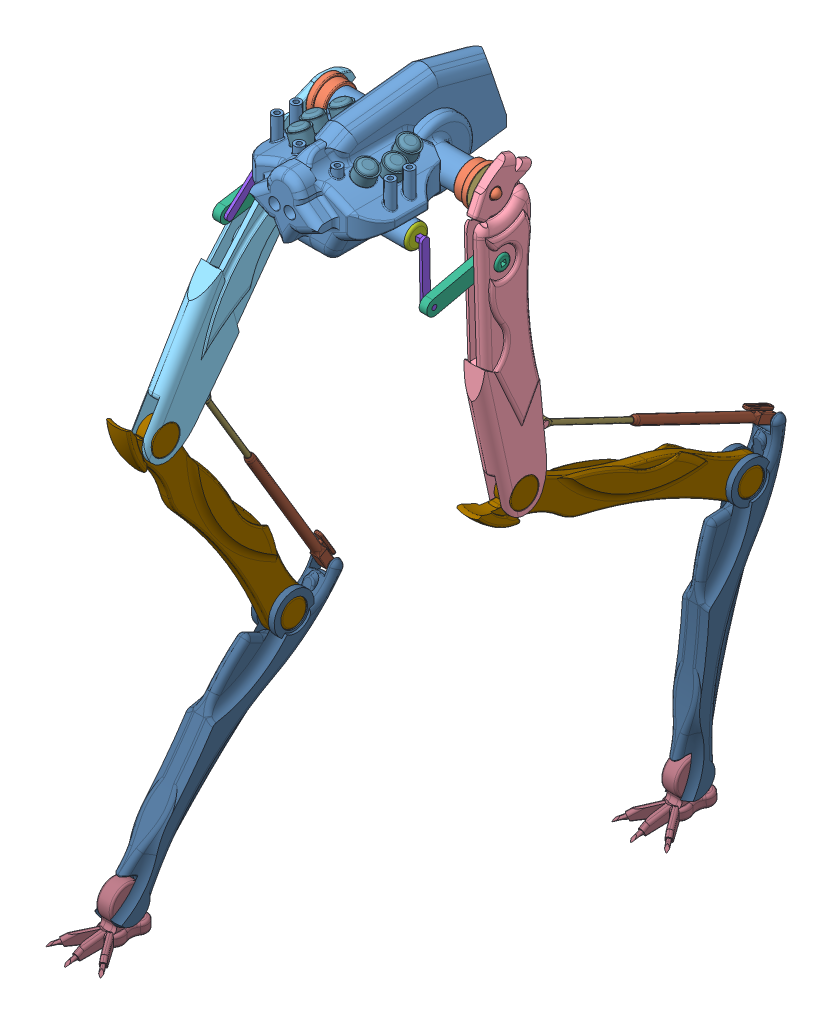
SolidWorks assembly canine rear end assembly, configuration Default. Lengths in mm.
Overall size (298.64 923.84 728.2).
29 component instances, 14 part files, 50 mates.
Components (placement in the parent):
- hind quarters-1: hind quarters [Default] at origin size (198.12 141.12 290.2)
- rear brushless hub motor-1: rear brushless hub motor [Default] at (86.36 -5.0738 -138.7243) x (1 0 0) z (0 -0.469696 0.882828) size (39.37 50.8 50.8)
- rear brushless hub motor cap-1: rear brushless hub motor cap [Default] at (106.68 -5.0738 -138.7243) x (1 0 0) z (0 0.469696 -0.882828) size (2.92 50.8 50.8)
- rear brushless hub motor cap-2: rear brushless hub motor cap [Default] at (-106.68 -5.0738 -138.7243) x (-1 0 0) z (0 0.867474 0.497482) size (2.92 50.8 50.8)
- rear brushless hub motor-2: rear brushless hub motor [Default] at (-86.36 -5.0738 -138.7243) x (-1 0 0) z (0 -0.867474 -0.497482) size (39.37 50.8 50.8)
- upper rear left leg-1: upper rear left leg [Default] at (107.315 -5.0738 -138.7243) x (1 0 0) z (0 -0.213473 0.976949) size (35.47 408.3 128.58)
- upper rear right leg-1: upper rear right leg [Default] at (-81.915 -5.0738 -138.7243) x (1 0 0) z (0 0.508175 0.861254) size (35.47 408.3 128.58)
- upper rear leg slider control bar-1: upper rear leg slider control bar [Default] at (110.236 -82.5296 -141.2052) x (1 0 0) z (0 -0.218855 0.975757) size (27.94 20.32 101.6)
- rear leg motion controller-1: rear leg motion controller [Default] at (66.04 -29.21 -60.599) x (1 0 0) z (0 -0.018232 0.999834) size (28.55 30.48 30.48)
- rear leg motion control rod-1: rear leg motion control rod [Default] at (102.108 -29.21 -60.599) x (1 0 0) z (0 0.999834 0.018232) size (26.67 10.16 81.28)
- rear leg motion controller-2: rear leg motion controller [Default] at (-66.04 -29.21 -60.599) x (-1 0 0) z (0 0.667442 -0.744662) size (28.55 30.48 30.48)
- rear leg motion control rod-2: rear leg motion control rod [Default] at (-102.108 -29.21 -60.599) x (-1 0 0) z (0 0.667442 -0.744662) size (26.67 10.16 81.28)
- upper rear leg slider control bar-2: upper rear leg slider control bar [Default] at (-110.236 -63.5304 -87.8482) x (-1 0 0) z (0 -0.161762 0.98683) size (27.94 20.32 101.6)
- middle rear leg-1: middle rear leg [Default] at (112.776 -362.7527 -170.5598) x (1 0 0) z (0 -0.909563 0.415567) size (41.3 413.23 74.4)
- middle rear leg-2: middle rear leg [Default] at (-112.776 -288.8817 81.2774) x (1 0 0) z (0 -0.513146 0.858301) size (41.3 413.23 74.4)
- lower rear leg-1: lower rear leg [Default] at (112.776 -499.973 -470.8973) x (1 0 0) z (0 0.252017 0.967723) size (49.71 405.22 76.89)
- lower rear leg-2: lower rear leg [Default] at (-112.776 -572.2927 -88.1635) x (1 0 0) z (0 0.701414 0.712754) size (49.71 405.22 76.89)
- lower rear leg motion sensor controller-1: lower rear leg motion sensor controller [Default] at (112.776 -451.3664 -510.4118) x (1 0 0) z (0 -0.902171 0.431378) size (20.32 209.55 18.41)
- lower rear leg motion sensor controller-2: lower rear leg motion sensor controller [Default] at (-112.776 -549.8979 -146.6654) x (1 0 0) z (0 -0.512749 0.858539) size (20.32 209.55 18.41)
- lower rear leg control rod-1: lower rear leg control rod [Default] at (112.776 -307.16 -208.8231) x (1 0 0) z (0 0.431378 0.902171) size (6.74 11.43 217.51)
- lower rear leg control rod-2: lower rear leg control rod [Default] at (-112.776 -276.3555 16.7037) x (1 0 0) z (0 0.858539 0.512749) size (6.74 11.43 217.51)
- rear claws-1: rear claws [Default] at (112.776 -806.1061 -398.4196) x (1 0 0) z (0 -0.032832 0.999461) size (73.09 64.37 105.72)
- rear claws-2: rear claws [Default] at (-112.776 -801.3851 127.4454) size (73.09 64.37 105.72)
- fluids container-1: fluids container [Default] at (25.9582 -13.2367 -42.5839) x (0.929939 -0.367713 -0.000069) z (-0.000069 -0.000362 1) size (26.67 57.15 26.67)
- fluids container-2: fluids container [Default] at (35.4101 -16.9633 -70.5239) x (0.929939 -0.367713 -0.000069) z (-0.000069 -0.000362 1) size (26.67 57.15 26.67)
- fluids container-3: fluids container [Default] at (25.9656 -13.2179 -98.4639) x (0.929939 -0.367713 -0.000069) z (-0.000069 -0.000362 1) size (26.67 57.15 26.67)
- fluids container-4: fluids container [Default] at (-25.9656 -13.2179 -98.4639) x (0.929939 0.367713 0.000069) z (0.000069 -0.000362 1) size (26.67 57.15 26.67)
- fluids container-5: fluids container [Default] at (-35.4101 -16.9633 -70.5239) x (0.929939 0.367713 0.000069) z (0.000069 -0.000362 1) size (26.67 57.15 26.67)
- fluids container-6: fluids container [Default] at (-25.9582 -13.2367 -42.5839) x (0.929939 0.367713 0.000069) z (0.000069 -0.000362 1) size (26.67 57.15 26.67)
Mates (geometry in assembly coordinates):
- Coincident1: coordinate: point of hind quarters-1; point of assembly
- Coincident2: coincident aligned: circle of hind quarters-1; circle of rear brushless hub motor-1
- Coincident3: coincident anti-aligned: circle of rear brushless hub motor-1; circle of rear brushless hub motor cap-1
- Coincident4: coincident anti-aligned: cylinder of rear brushless hub motor-1 through (119.38 -5.0738 -138.7243) axis (-1 0 0) radius 7.62; circle of rear brushless hub motor cap-1
- Coincident5: coincident anti-aligned: circle of hind quarters-1; circle of rear brushless hub motor-2
- Coincident6: coincident anti-aligned: circle of rear brushless hub motor cap-2; circle of rear brushless hub motor-2
- Concentric1: concentric anti-aligned: circle of rear brushless hub motor cap-2; cylinder of rear brushless hub motor-2 through (-119.38 -5.0738 -138.7243) axis (1 0 0) radius 7.62
- Concentric3: concentric aligned: cylinder of rear brushless hub motor-1 through (119.38 -5.0738 -138.7243) axis (-1 0 0) radius 7.62; cylinder of upper rear left leg-1 through (119.507 -5.0738 -138.7243) axis (-1 0 0) radius 7.62
- Coincident8: coincident anti-aligned: plane of rear brushless hub motor cap-1 through (107.315 -5.0738 -138.7243) normal (1 0 0); plane of upper rear left leg-1 through (107.315 -5.0738 -138.7243) normal (-1 0 0)
- Concentric4: concentric aligned: cylinder of rear brushless hub motor-2 through (-119.38 -5.0738 -138.7243) axis (1 0 0) radius 7.62; cylinder of upper rear right leg-1 through (-119.507 -5.0738 -138.7243) axis (1 0 0) radius 7.62
- Coincident9: coincident anti-aligned: plane of rear brushless hub motor cap-2 through (-107.315 -5.0738 -138.7243) normal (-1 0 0); plane of upper rear right leg-1 through (-107.315 -5.0738 -138.7243) normal (1 0 0)
- Coincident10: coincident aligned: plane of upper rear left leg-1 through (100.076 -46.4388 -142.2178) normal (-1 0 0); plane of upper rear leg slider control bar-1 through (100.076 -82.5296 -141.2052) normal (-1 0 0)
- Coincident11: coincident aligned: circle of hind quarters-1; circle of rear leg motion controller-1
- Concentric5: concentric anti-aligned: cylinder of upper rear leg slider control bar-1 through (100.076 -100.3182 -61.8956) axis (1 0 0) radius 3.175; cylinder of rear leg motion control rod-1 through (115.316 -100.3182 -61.8956) axis (-1 0 0) radius 3.175
- Concentric7: concentric aligned: cylinder of upper rear left leg-1 through (126.746 -82.5296 -141.2052) axis (-1 0 0) radius 10.16; cylinder of upper rear leg slider control bar-1 through (120.396 -82.5296 -141.2052) axis (-1 0 0) radius 10.16
- Coincident13: coincident anti-aligned: plane of rear leg motion controller-1 through (81.8896 -32.4424 -57.4824) normal (0 0.018232 -0.999834); plane of rear leg motion control rod-1 through (88.646 -26.0934 -57.3666) normal (0 -0.018232 0.999834)
- Coincident14: coincident anti-aligned: plane of rear leg motion controller-1 through (81.8896 -32.4424 -57.4824) normal (0 0.999834 0.018232); plane of rear leg motion control rod-1 through (88.646 -32.3266 -63.8313) normal (0 -0.999834 -0.018232)
- LimitAngle1: limit planar angle = 1.552564 rad aligned: plane of assembly through (0 0 0) normal (0 1 0); plane of rear leg motion control rod-1 through (101.346 -29.1174 -65.6781) normal (0 0.018232 -0.999834)
- Coincident15: coincident anti-aligned: circle of hind quarters-1; circle of rear leg motion controller-2
- Parallel1: parallel anti-aligned: plane of rear leg motion controller-2 through (-94.5896 -29.21 -60.599) normal (-1 0 0); plane of rear leg motion control rod-2 through (-101.346 -29.21 -60.599) normal (1 0 0)
- Coincident17: coincident anti-aligned: plane of rear leg motion controller-2 through (-81.8896 -24.7266 -60.8441) normal (0 -0.744662 -0.667442); plane of rear leg motion control rod-2 through (-88.646 -24.7266 -60.8441) normal (0 0.744662 0.667442)
- Coincident18: coincident anti-aligned: plane of rear leg motion controller-2 through (-81.8896 -33.6934 -60.3538) normal (0 0.667442 -0.744662); plane of rear leg motion control rod-2 through (-88.646 -28.9648 -56.1155) normal (0 -0.667442 0.744662)
- Coincident19: coincident aligned: circle of rear leg motion control rod-2; circle of upper rear leg slider control bar-2
- Coincident20: coincident anti-aligned: plane of upper rear right leg-1 through (-105.156 -126.6891 -196.1889) normal (-1 0 0); plane of upper rear leg slider control bar-2 through (-105.156 -76.6785 -7.6386) normal (1 0 0)
- Concentric8: concentric aligned: cylinder of upper rear right leg-1 through (-126.746 -63.5304 -87.8482) axis (1 0 0) radius 10.16; cylinder of upper rear leg slider control bar-2 through (-120.396 -63.5304 -87.8482) axis (1 0 0) radius 10.16
- LimitAngle2: limit planar angle = 2.410824 rad aligned: plane of rear leg motion control rod-2 through (-101.346 -32.9929 -63.9896) normal (0 -0.744662 -0.667442); plane of assembly through (0 0 0) normal (0 1 0)
- Concentric9: concentric anti-aligned: cylinder of upper rear left leg-1 through (62.484 -362.7527 -170.5598) axis (1 0 0) radius 19.05; cylinder of middle rear leg-1 through (126.746 -362.7527 -170.5598) axis (-1 0 0) radius 19.05
- Coincident21: coincident aligned: plane of upper rear left leg-1 through (126.746 -343.3031 -126.1387) normal (1 0 0); plane of middle rear leg-1 through (126.746 -362.7527 -170.5598) normal (1 0 0)
- Coincident22: coincident aligned: plane of upper rear right leg-1 through (-98.806 -244.4063 100.6027) normal (1 0 0); plane of middle rear leg-2 through (-98.806 -288.8817 81.2774) normal (1 0 0)
- Concentric10: concentric anti-aligned: cylinder of upper rear right leg-1 through (-126.746 -288.8817 81.2774) axis (1 0 0) radius 19.05; cylinder of middle rear leg-2 through (-98.806 -288.8817 81.2774) axis (-1 0 0) radius 19.05
- Concentric11: concentric anti-aligned: cylinder of middle rear leg-1 through (97.536 -499.973 -470.8973) axis (1 0 0) radius 17.78; cylinder of lower rear leg-1 through (128.016 -499.973 -470.8973) axis (-1 0 0) radius 17.78
- Coincident23: coincident aligned: plane of middle rear leg-1 through (128.016 -499.973 -470.8973) normal (1 0 0); plane of lower rear leg-1 through (128.016 -499.973 -470.8973) normal (1 0 0)
- Concentric12: concentric anti-aligned: cylinder of middle rear leg-2 through (-128.016 -572.2927 -88.1635) axis (1 0 0) radius 17.78; cylinder of lower rear leg-2 through (-97.536 -572.2927 -88.1635) axis (-1 0 0) radius 17.78
- Coincident24: coincident aligned: plane of middle rear leg-2 through (-97.536 -572.2927 -88.1635) normal (1 0 0); plane of lower rear leg-2 through (-97.536 -572.2927 -88.1635) normal (1 0 0)
- LimitAngle3: limit planar angle = 1.396994 rad aligned: plane of middle rear leg-1 through (112.776 -362.7527 -170.5598) normal (0 -0.909563 0.415567); plane of lower rear leg-1 through (112.776 -499.973 -470.8973) normal (0 0.252017 0.967723)
- LimitAngle4: limit planar angle = 1.316226 rad aligned: plane of middle rear leg-2 through (-112.776 -288.8817 81.2774) normal (0 -0.513146 0.858301); plane of lower rear leg-2 through (-112.776 -572.2927 -88.1635) normal (0 0.701414 0.712754)
- LimitAngle5: limit planar angle = 0.927101 rad aligned: plane of upper rear left leg-1 through (107.315 -5.0738 -138.7243) normal (0 -0.213473 0.976949); plane of middle rear leg-1 through (112.776 -362.7527 -170.5598) normal (0 -0.909563 0.415567)
- LimitAngle6: limit planar angle = 1.071911 rad aligned: plane of upper rear right leg-1 through (-81.915 -5.0738 -138.7243) normal (0 0.508175 0.861254); plane of middle rear leg-2 through (-112.776 -288.8817 81.2774) normal (0 -0.513146 0.858301)
- Coincident25: coincident aligned: circle of lower rear leg-1; circle of lower rear leg motion sensor controller-1
- Coincident26: coincident aligned: circle of lower rear leg-2; circle of lower rear leg motion sensor controller-2
- Concentric13: concentric anti-aligned: cylinder of lower rear leg motion sensor controller-1 through (112.776 -363.1625 -325.9449) axis (0 -0.431378 -0.902171) radius 5.715; cylinder of lower rear leg control rod-1 through (112.776 -398.5245 -399.8999) axis (0 0.431378 0.902171) radius 3.175
- Coincident27: coincident aligned: circle of upper rear right leg-1; circle of lower rear leg control rod-2
- Concentric15: concentric anti-aligned: cylinder of lower rear leg motion sensor controller-2 through (-112.776 -374.3525 -41.8235) axis (0 -0.858539 -0.512749) radius 5.715; cylinder of lower rear leg control rod-2 through (-112.776 -458.1911 -91.8949) axis (0 0.858539 0.512749) radius 3.175
- Coincident28: coincident anti-aligned: circle of upper rear left leg-1; circle of lower rear leg control rod-1
- Coincident29: coincident aligned: circle of lower rear leg-1; circle of rear claws-1
- Coincident30: coincident aligned: plane of upper rear leg slider control bar-1 through (115.316 -100.3182 -61.8956) normal (1 0 0); plane of rear leg motion control rod-1 through (115.316 -100.3182 -61.8956) normal (1 0 0)
- Coincident31: coincident anti-aligned: circle of lower rear leg-2; circle of rear claws-2
- Coincident32: coincident anti-aligned: circle of hind quarters-1; circle of fluids container-1
- Coincident33: coincident anti-aligned: circle of hind quarters-1; circle of fluids container-2
- Coincident34: coincident anti-aligned: circle of hind quarters-1; circle of fluids container-3
